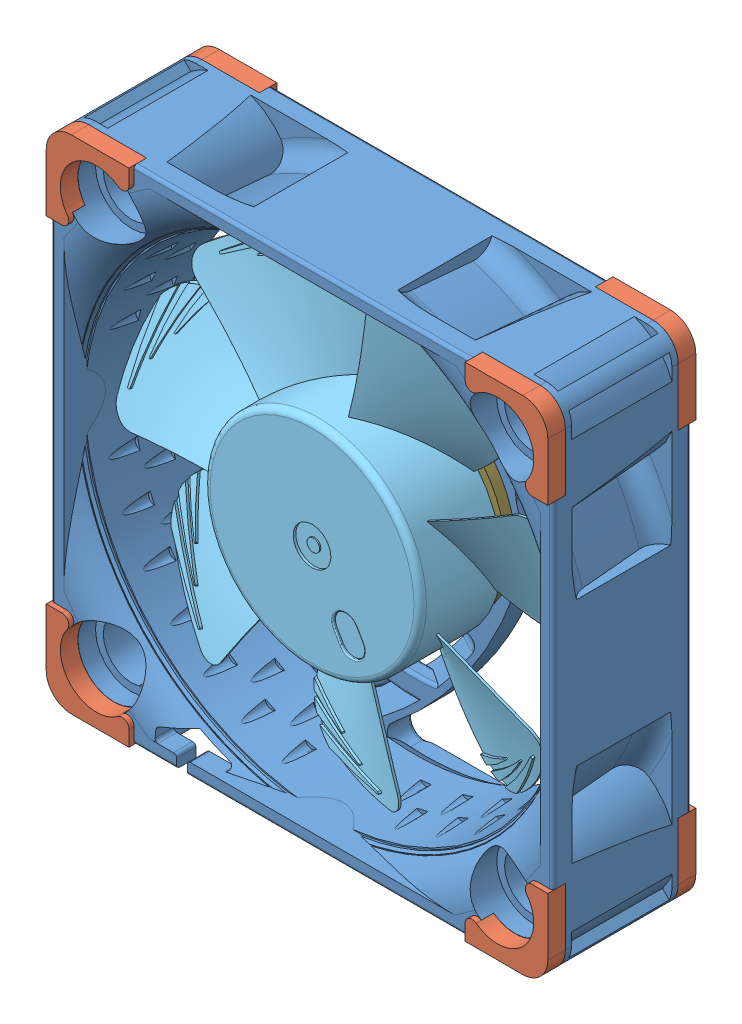
SolidWorks assembly NF-A4x10 FLX, configuration Predeterminado. Lengths in mm.
Overall size (43.47 43.5 12.76).
34 component instances, 19 part files, 30 mates.
Components (placement in the parent):
- Case-1: Case [Predeterminado] at origin size (40.18 40.19 12.76)
- Silent block-1: Silent block [Predeterminado] at (-16 16 10) size (6.6 6.6 1.4)
- Magnet-1: Magnet [Predeterminado] at (0 0 0.4) size (4.08 4.08 0.9)
- Back plate-1: Back plate [Predeterminado] at origin size (15.2 15.2 0.4)
- Impeller-1: Impeller [Predeterminado] at (0 0 10.2) x (0.232084 -0.972696 0) z (0 0 1) size (36.12 36.07 6.94)
- Magnetic screen-1: Magnetic screen [Predeterminado] at (0 0 3.7) x (0.411264 -0.911516 0) z (0 0 1) size (16.85 16.85 6)
- Rotor-1: Rotor [Predeterminado] at (0 0 3.7) x (-0.165519 0.986207 0) z (0 0 -1) size (16.45 16.45 6.1)
- Shaft-1: Shaft [Predeterminado] at (0 0 9.8) x (0.165519 -0.986207 0) z (0 0 1) size (2.38 2.37 7.5)
- Oil Bearing-1: Oil Bearing [Predeterminado] at (0 0 2) x (1 0 0) z (0 0 -1) size (5 5 5)
  - Bearing-1: Bearing [Predeterminado] at origin size (5 5 5)
  - Bearing gasket-1: Bearing gasket [Predeterminado] at (0 0 -1.3) size (2 2 0.5)
  - Oil-1: Oil [Predeterminado] at (0 0 -4.5) size (4 4 2.7)
  - Bearing gasket-2: Bearing gasket [Predeterminado] at (0 0 -4.5) size (2 2 0.5)
- Brushless motor-1: Brushless motor [Predeterminado] at (0 0 2) size (16 16 8.48)
  - Board-1: Board [Predeterminado] at origin size (16 16 0.8)
  - Stator-1: Stator [Predeterminado] at (0 0 3.55) size (11.93 12 5.5)
  - Hall Effect sensor-1: Hall Effect sensor [WE] at (-5.3023 -0.9391 0) x (-0.233503 0.972356 0) z (-0.972356 -0.233503 0) size (6.3 1.6 2.6)
  - Controller-1: Controller [Predeterminado] at (5.1574 2.3195 0) x (0.319288 -0.947658 0) z (0.947658 0.319288 0) size (4.81 0.99 3)
  - Coil-1: Coil [Predeterminado] at (0 -5.01 1.29) x (-1 0 0) z (0 1 0) size (2.38 5.38 1.58)
  - Pieza2^Brushless motor-1: Pieza2^Brushless motor [Predeterminado] at origin size (10.72 12.51 6.88) (virtual)
  - Pieza3^Brushless motor-1: Pieza3^Brushless motor [Predeterminado] at (0 0 0.8) size (4.1 0.74 1.7) (virtual)
  - Coil-2: Coil [Predeterminado] at (-4.3388 -2.505 1.29) x (-0.5 0.866025 0) z (0.866025 0.5 0) size (2.38 5.38 1.58)
  - Coil-3: Coil [Predeterminado] at (-4.3388 2.505 1.29) x (0.5 0.866025 0) z (0.866025 -0.5 0) size (2.38 5.38 1.58)
  - Coil-4: Coil [Predeterminado] at (0 5.01 1.29) x (1 0 0) z (0 -1 0) size (2.38 5.38 1.58)
  - Coil-5: Coil [Predeterminado] at (4.3388 2.505 1.29) x (0.5 -0.866025 0) z (-0.866025 -0.5 0) size (2.38 5.38 1.58)
  - Coil-6: Coil [Predeterminado] at (4.3388 -2.505 1.29) x (-0.5 -0.866025 0) z (-0.866025 0.5 0) size (2.38 5.38 1.58)
- Wires^NF-A4x10 FLX-1: Wires^NF-A4x10 FLX [Predeterminado] at (0 0 2) x (-1 0 0) z (0 0 -1) size (13.5 12.74 7.88) (virtual)
- Silent block-2: Silent block [Predeterminado] at (16 16 10) x (0 -1 0) z (0 0 1) size (6.6 6.6 1.4)
- Silent block-3: Silent block [Predeterminado] at (16 -16 10) x (-1 0 0) z (0 0 1) size (6.6 6.6 1.4)
- Silent block-4: Silent block [Predeterminado] at (-16 -16 10) x (0 1 0) z (0 0 1) size (6.6 6.6 1.4)
- Silent block-5: Silent block [Predeterminado] at (-16 16 -0.4) size (6.6 6.6 1.4)
- Silent block-6: Silent block [Predeterminado] at (16 16 -0.4) x (0 -1 0) z (0 0 1) size (6.6 6.6 1.4)
- Silent block-7: Silent block [Predeterminado] at (16 -16 -0.4) x (-1 0 0) z (0 0 1) size (6.6 6.6 1.4)
- Silent block-8: Silent block [Predeterminado] at (-16 -16 -0.4) x (0 1 0) z (0 0 1) size (6.6 6.6 1.4)
Mates (geometry in assembly coordinates):
- Coincidente1: coincident aligned: plane of Case-1 through (0 0 0) normal (0 0 1)
- Coincidente2: coincident aligned: plane of Case-1 through (0 0 0) normal (0 1 0)
- Coincidente3: coincident aligned: plane of Case-1 through (0 0 0) normal (1 0 0)
- Concéntrica1: concentric anti-aligned: cylinder of Case-1 through (-16 16 8.6) axis (0 0 1) radius 2.875; cylinder of Silent block-1 through (-16 16 11.4) axis (0 0 -1) radius 2.875
- Coincidente4: coincident anti-aligned: plane of Case-1 through (-13.4 -18 11) normal (-1 0 0); plane of Silent block-1 through (-13.4 20 11.4) normal (1 0 0)
- Coincidente5: coincident anti-aligned: plane of Case-1 through (-18 -18 10) normal (0 0 1); plane of Silent block-1 through (-18.7563 13.9563 10) normal (0 0 -1)
- Concéntrica2: concentric aligned: cylinder of Case-1 through (0 0 1.4) axis (0 0 -1) radius 2.1; cylinder of Magnet-1 through (0 0 1.3) axis (0 0 -1) radius 2.04
- Coincidente6: coincident aligned: plane of Case-1 through (0 0 0.4) normal (0 0 -1); plane of Magnet-1 through (0 0 0.4) normal (0 0 -1)
- Concéntrica3: concentric aligned: cylinder of Magnet-1 through (0 0 1.3) axis (0 0 -1) radius 2.04; cylinder of Back plate-1 through (0 0 0.4) axis (0 0 -1) radius 7.6
- Coincidente7: coincident anti-aligned: plane of Case-1 through (0 0 0.4) normal (0 0 -1); plane of Back plate-1 through (0 0 0.4) normal (0 0 1)
- Coincidente8: coincident aligned: plane of Magnet-1 through (0 0 0.4) normal (0 1 0)
- Coincidente9: coincident aligned: plane of Back plate-1 through (0 0 0) normal (0 1 0)
- Concéntrica4: concentric anti-aligned: cone of Case-1 through (0 0 0) axis (0 0 -1); cylinder of Impeller-1 through (0 0 10.2) axis (0 0 1) radius 8.625
- Concéntrica5: concentric anti-aligned: cylinder of Impeller-1 through (0 0 10.2) axis (0 0 1) radius 8.425; cylinder of Gasket-1 through (0 0 9.7) axis (0 0 -1) radius 8.425
- Coincidente10: coincident aligned: plane of Impeller-1 through (2.0017 -8.3895 3.7) normal (0 0 -1); plane of Gasket-1 through (0 0 3.7) normal (0 0 -1)
- Concéntrica6: concentric aligned: cylinder of Gasket-1 through (0 0 9.7) axis (0 0 -1) radius 8.225; cylinder of Rotor-1 through (0 0 9.8) axis (0 0 -1) radius 8.225
- Coincidente11: coincident aligned: plane of Gasket-1 through (0 0 3.7) normal (0 0 -1); plane of Rotor-1 through (0 0 3.7) normal (0 0 -1)
- Concéntrica7: concentric aligned: cylinder of Impeller-1 through (0 0 9.8) axis (0 0 1) radius 1; cylinder of Shaft-1 through (0 0 2.3) axis (0 0 1) radius 1
- Coincidente12: coincident anti-aligned: plane of Impeller-1 through (0 0 9.8) normal (0 0 -1); plane of Shaft-1 through (0 0 9.8) normal (0 0 1)
- Distancia1: distance = 0.8 mm aligned: plane of Impeller-1 through (0 0 10.2) normal (0 0 1); plane of Case-1 through (-18.7563 -13.9563 11) normal (0 0 1)
- Concéntrica8: concentric anti-aligned: cylinder of Case-1 through (0 0 1.2) axis (0 0 1) radius 3.1; cylinder of Oil Bearing-1/Bearing-1 through (0 0 2) axis (0 0 -1) radius 2.5
- Coincidente13: coincident anti-aligned: plane of Case-1 through (-8.3202 -3.0887 2) normal (0 0 1); plane of Oil Bearing-1/Bearing-1 through (-1.5 0 2) normal (0 0 -1)
- Concéntrica9: concentric aligned: cylinder of Oil Bearing-1/Bearing-1 through (0 0 2) axis (0 0 -1) radius 2.5; cylinder of Brushless motor-1/Stator-1 through (0 0 8.3) axis (0 0 -1) radius 2.5
- Coincidente14: coincident anti-aligned: plane of Case-1 through (-8.3202 -3.0887 2) normal (0 0 1); plane of Brushless motor-1/Board-1 through (0 0 2) normal (0 0 -1)
- Ancho3: width anti-aligned: plane of Case-1 through (-4.4294 1.6359 11.6693) normal (-0.972356 -0.233503 0); plane of Case-1 through (-7.3427 1.3477 11.6693) normal (0.972356 0.233503 0); plane of Brushless motor-1/Hall Effect sensor-1 through (-3.5362 -2.7261 0.4) normal (0.972356 0.233503 0); plane of Brushless motor-1/Hall Effect sensor-1 through (-6.0643 -3.3332 0.4) normal (-0.972356 -0.233503 0)
- Ancho4: width anti-aligned: plane of Brushless motor-1/Hall Effect sensor-1 through (-6.0643 -3.3332 0.4) normal (0.233503 -0.972356 0); plane of Brushless motor-1/Hall Effect sensor-1 through (-7.0684 0.848 0.4) normal (-0.233503 0.972356 0); plane of Case-1 through (-3.2619 -3.2258 11.6693) normal (-0.233503 0.972356 0); plane of Case-1 through (-5.435 1.8058 11.6693) normal (0.233503 -0.972356 0)
- EnPosición1: in place: plane of ? through (0 0 2) normal (0 0 -1); plane of Wires^NF-A4x10 FLX-1 through (0 0 2) normal (0 0 -1); moOrthogonalPlaneRef_w of ? through (0 0 2) normal (0 0 -1); plane of Wires^NF-A4x10 FLX-1 through (0 0 2) normal (0 1 0); plane of ? through (0 0 2) normal (0 0 -1); plane of Wires^NF-A4x10 FLX-1 through (0 0 2) normal (-1 0 0); plane of ? through (0 0 2) normal (0 0 -1); unknown of Wires^NF-A4x10 FLX-1
- Coincidente16: coincident aligned: plane of ?; plane of ?
- Coincidente17: coincident aligned: moOrthogonalPlaneRef_w of Brushless motor-1/Board-1 through (0 0 2) normal (0 1 0); plane of Pieza4^NF-A4x10 FLX-1 through (0 0 2) normal (0 1 0)
- Coincidente18: coincident anti-aligned: moOrthogonalPlaneRef_w of Brushless motor-1/Board-1 through (0 0 2) normal (1 0 0); plane of Pieza4^NF-A4x10 FLX-1 through (0 0 2) normal (-1 0 0)
